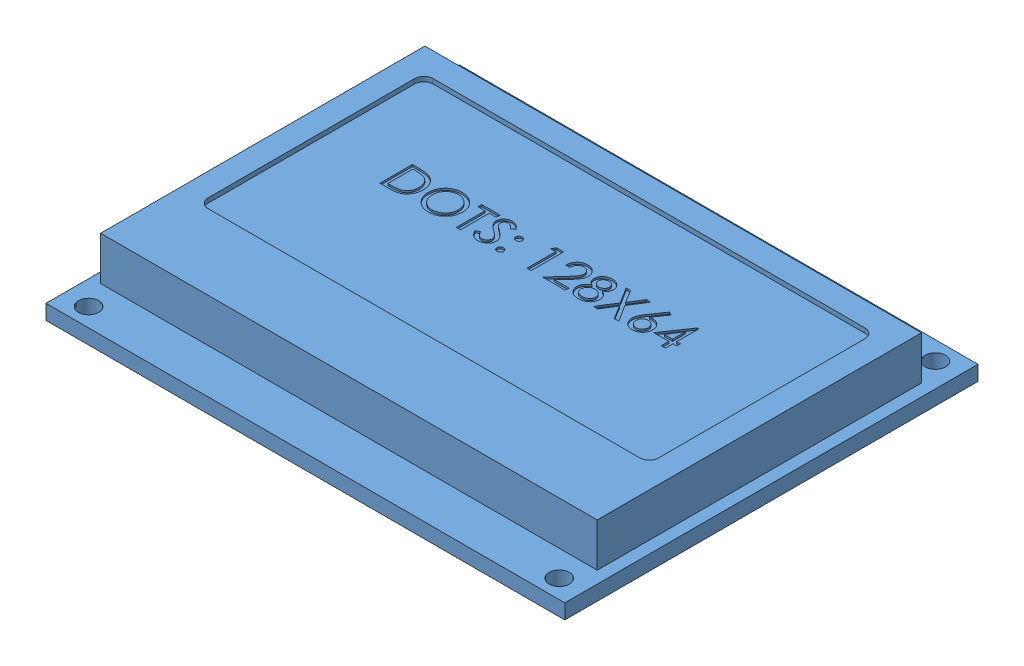
SolidWorks assembly 12864, configuration Default. Lengths in mm.
Overall size (56 20.1 44.6).
7 component instances, 3 part files, 4 mates.
Components (placement in the parent):
- 12864-1: 12864 [Default] at origin size (56 6.3 44.6)
- PBS-4.step-1: PBS-4.step [Default] at (-11.1083 -10.8 -15.3) x (0.999955 0 0.009532) z (0 1 0) size (10.16 2.54 11.5)
- 4x_Male_Pin_2.54_mm.STEP-1: 4x_Male_Pin_2.54_mm.STEP [Default] at (-6.7993 5.2562 -26.5781) x (-0.999955 0 -0.009532) z (-0.009532 0 0.999955) size (10.16 11.1 2.4)
  - 1_Male_Pin_2.54_mm.STEP-1: 1_Male_Pin_2.54_mm.STEP [Default] at (3.8763 2.2562 11.0637) size (2.54 11.1 2.4)
  - 1_Male_Pin_2.54_mm.STEP-2: 1_Male_Pin_2.54_mm.STEP [Default] at (1.3363 2.2562 11.0637) size (2.54 11.1 2.4)
  - 1_Male_Pin_2.54_mm.STEP-3: 1_Male_Pin_2.54_mm.STEP [Default] at (-1.2037 2.2562 11.0637) size (2.54 11.1 2.4)
  - 1_Male_Pin_2.54_mm.STEP-4: 1_Male_Pin_2.54_mm.STEP [Default] at (-3.7437 2.2562 11.0637) size (2.54 11.1 2.4)
Mates (geometry in assembly coordinates):
- Coincident1: coincident anti-aligned: plane of 12864-1 through (0 0 0) normal (0 -1 0); plane of 4x_Male_Pin_2.54_mm.STEP-1/1_Male_Pin_2.54_mm.STEP-4 through (-3.1612 0 -15.4793) normal (0 1 0)
- Coincident4: coincident anti-aligned: plane of PBS-4.step-1 through (-11.1083 -2.3 -15.3) normal (0 1 0); plane of 4x_Male_Pin_2.54_mm.STEP-1/1_Male_Pin_2.54_mm.STEP-4 through (-3.1612 -2.3 -15.4793) normal (0 -1 0)
- Coincident5: coincident aligned: plane of PBS-4.step-1 through (-12.3903 -10.8 -14.0422) normal (-0.009532 0 0.999955); plane of 4x_Male_Pin_2.54_mm.STEP-1/1_Male_Pin_2.54_mm.STEP-4 through (-4.7707 -2.3 -13.9695) normal (-0.009532 0 0.999955)
- Coincident6: coincident: plane of PBS-4.step-1 through (-2.2308 -10.8 -13.9453) normal (0.999955 0 0.009532); line of 4x_Male_Pin_2.54_mm.STEP-1/1_Male_Pin_2.54_mm.STEP-4 through (-2.2103 -2.3 -16.0952) axis (0 1 0)
